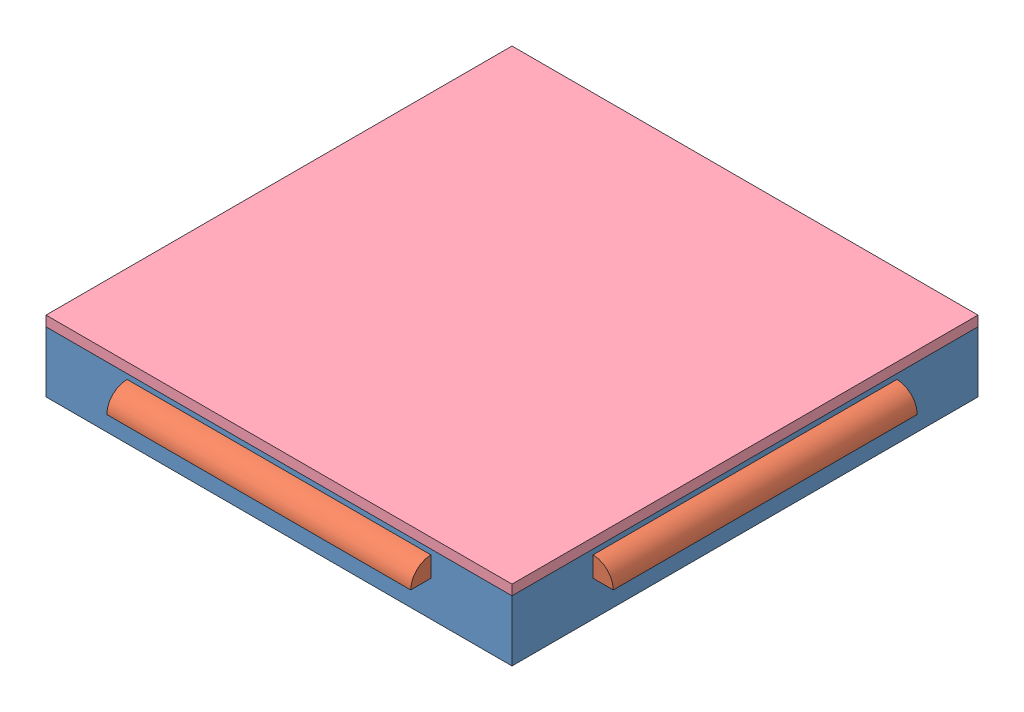
SolidWorks assembly finalassesm, configuration Default. Lengths in mm.
Overall size (50 9.25 50).
11 component instances, 5 part files, 22 mates.
Components (placement in the parent):
- modular_bot-2.2-1: modular_bot-2.2 [Default] at (40.8044 22.7886 12.1799) size (46 6 46)
- modular_bot-2.1-1: modular_bot-2.1 [Default] at (3.8044 26.2886 17.1799) size (8 2 30)
- modular_bot-2.1-4: modular_bot-2.1 [Default] at (35.8044 26.2886 15.1799) x (0 0 1) z (-1 0 0) size (8 2 30)
- modular_bot-2.1-6: modular_bot-2.1 [Default] at (37.8044 26.2886 47.1799) x (-1 0 0) z (0 0 -1) size (8 2 30)
- modular_bot-2.1-8: modular_bot-2.1 [Default] at (5.8044 26.2886 49.1799) x (0 0 -1) z (1 0 0) size (8 2 30)
- modular_bot-2.3-1: modular_bot-2.3 [Default] at (25.8044 27.5438 32.0993) x (0 -1 0) z (0 0 1) size (1.28 12.5 1.44)
- modular_bot-2.3-11: modular_bot-2.3 [Default] at (20.6677 27.2225 27.1799) x (0 -1 0) z (1 0 0) size (1.28 12.5 1.44)
- modular_bot-2.3-13: modular_bot-2.3 [Default] at (20.6677 27.2225 49.1934) x (0.134083 -0.99097 0) z (0.99097 0.134083 0) size (1.28 12.5 1.44)
- modular_bot-2.3-15: modular_bot-2.3 [Default] at (3.8328 27.5438 32.0993) x (0 -1 0) z (0 0 1) size (1.28 12.5 1.44)
- modular_bot-2.4-1: modular_bot-2.4 [Default] at (20.8044 28.7886 32.1799) size (46 1 46)
- modular_bot-2.5-1: modular_bot-2.5 [Default] at (20.8044 20.5386 32.1799) x (-0.033102 0 -0.999452) z (0.999452 0 -0.033102) size (2 7.5 2)
Mates (geometry in assembly coordinates):
- Coincident1: coincident anti-aligned: plane of modular_bot-2.2-1 through (-2.1956 28.2886 17.1799) normal (0 0 1); plane of modular_bot-2.1-1 through (3.8044 28.2886 17.1799) normal (0 0 -1)
- Coincident2: coincident anti-aligned: plane of modular_bot-2.2-1 through (-2.1956 28.2886 17.1799) normal (0 -1 0); plane of modular_bot-2.1-1 through (3.8044 28.2886 17.1799) normal (0 1 0)
- Coincident3: coincident: plane of modular_bot-2.2-1 through (-2.1956 22.7886 12.1799) normal (-1 0 0); line of modular_bot-2.1-1 through (-2.1956 28.2886 17.1799) axis (0 0 1)
- Coincident9: coincident anti-aligned: plane of modular_bot-2.2-1 through (35.8044 28.2886 9.1799) normal (-1 0 0); plane of modular_bot-2.1-4 through (35.8044 28.2886 15.1799) normal (1 0 0)
- Coincident10: coincident anti-aligned: plane of modular_bot-2.2-1 through (5.8044 28.2886 9.1799) normal (0 -1 0); plane of modular_bot-2.1-4 through (35.8044 28.2886 15.1799) normal (0 1 0)
- Coincident11: coincident: plane of modular_bot-2.2-1 through (40.8044 22.7886 9.1799) normal (0 0 -1); line of modular_bot-2.1-4 through (35.8044 28.2886 9.1799) axis (-1 0 0)
- Coincident12: coincident anti-aligned: plane of modular_bot-2.2-1 through (43.8044 28.2886 47.1799) normal (0 0 -1); plane of modular_bot-2.1-6 through (37.8044 28.2886 47.1799) normal (0 0 1)
- Coincident13: coincident anti-aligned: plane of modular_bot-2.2-1 through (43.8044 28.2886 47.1799) normal (0 -1 0); plane of modular_bot-2.1-6 through (37.8044 28.2886 47.1799) normal (0 1 0)
- Coincident14: coincident: plane of modular_bot-2.2-1 through (43.8044 22.7886 55.1799) normal (1 0 0); line of modular_bot-2.1-6 through (43.8044 28.2886 47.1799) axis (0 0 -1)
- Coincident15: coincident anti-aligned: plane of modular_bot-2.2-1 through (5.8044 28.2886 55.1799) normal (1 0 0); plane of modular_bot-2.1-8 through (5.8044 28.2886 49.1799) normal (-1 0 0)
- Coincident16: coincident anti-aligned: plane of modular_bot-2.2-1 through (35.8044 28.2886 55.1799) normal (0 -1 0); plane of modular_bot-2.1-8 through (5.8044 28.2886 49.1799) normal (0 1 0)
- Coincident17: coincident: plane of modular_bot-2.2-1 through (40.8044 22.7886 55.1799) normal (0 0 1); line of modular_bot-2.1-8 through (5.8044 28.2886 55.1799) axis (1 0 0)
- Perpendicular1: perpendicular: plane of modular_bot-2.1-6 through (37.8044 28.2886 47.1799) normal (-1 0 0); line of modular_bot-2.3-1 through (25.8044 27.5438 32.0993) axis (1 0 0)
- Coincident19: coincident anti-aligned: point of modular_bot-2.3-1; plane of modular_bot-2.1-6 through (37.8044 28.2886 47.1799) normal (-1 0 0)
- Perpendicular8: perpendicular: plane of modular_bot-2.1-4 through (35.8044 28.2886 15.1799) normal (0 0 1); line of modular_bot-2.3-11 through (20.6677 27.2225 27.1799) axis (0 0 -1)
- Coincident27: coincident anti-aligned: plane of modular_bot-2.1-4 through (35.8044 28.2886 15.1799) normal (0 0 1); point of modular_bot-2.3-11
- Coincident29: coincident aligned: line of modular_bot-2.3-11 through (20.6677 27.2225 27.1799) axis (0 0 -1); line of modular_bot-2.3-13 through (20.6677 27.2225 49.1934) axis (0 0 -1)
- Coincident30: coincident aligned: line of modular_bot-2.3-1 through (25.8044 27.5438 32.0993) axis (1 0 0); line of modular_bot-2.3-15 through (3.8328 27.5438 32.0993) axis (1 0 0)
- Coincident36: coincident anti-aligned: plane of modular_bot-2.2-1 through (43.8044 28.7886 55.1799) normal (0 1 0); plane of modular_bot-2.4-1 through (20.8044 28.7886 32.1799) normal (0 -1 0)
- Coincident37: coincident anti-aligned: line of modular_bot-2.2-1 through (43.8044 22.7886 55.1799) axis (0 1 0); line of modular_bot-2.4-1 through (43.8044 29.7886 55.1799) axis (0 -1 0)
- Concentric2: concentric anti-aligned: cylinder of modular_bot-2.2-1 through (20.8044 22.7886 32.1799) axis (0 1 0) radius 0.8; cylinder of modular_bot-2.5-1 through (20.8044 25.7886 32.1799) axis (0 -1 0) radius 0.8
- Coincident39: coincident anti-aligned: plane of modular_bot-2.2-1 through (40.8044 22.7886 12.1799) normal (0 -1 0); plane of modular_bot-2.5-1 through (20.8044 22.7886 32.1799) normal (0 1 0)
